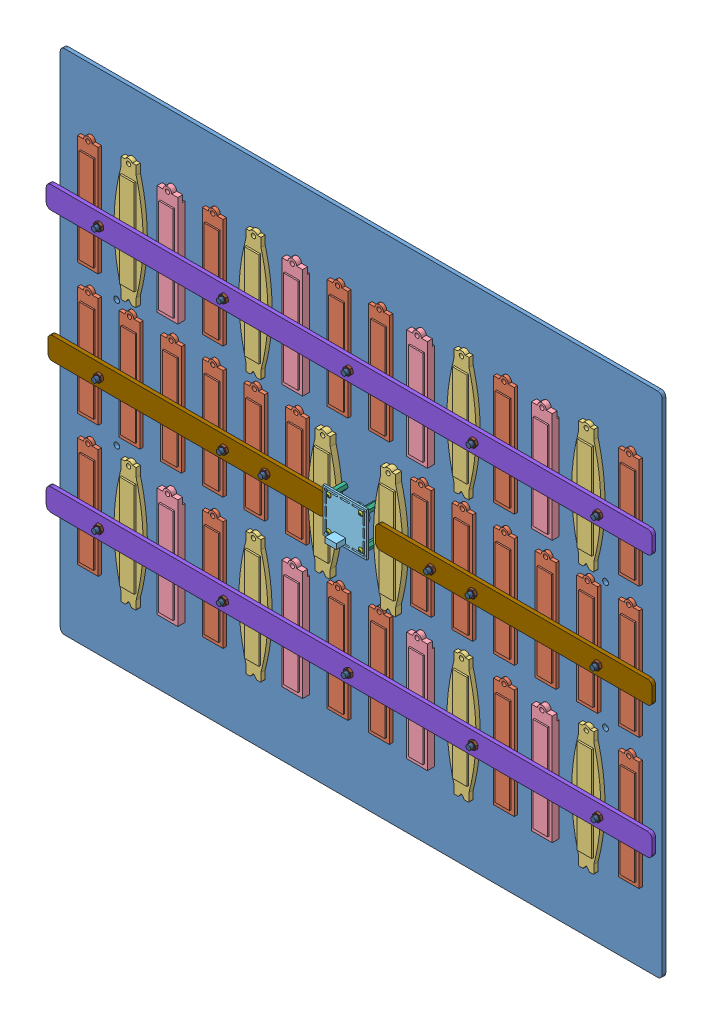
SolidWorks assembly light_panel_assembly, configuration Default. Lengths in mm.
Overall size (528.83 443.28 29.53).
93 component instances, 11 part files, 117 mates.
Components (placement in the parent):
- light_panel-2: light_panel [Default] at (-165.7065 6.3384 576.4657) size (525.46 443.28 3.17)
- ge_light_red-29: ge_light_red [Default] at (-258.0598 168.151 582.5617) x (0 1 0) z (-1 0 0) size (99.54 9.65 18.11)
- ge_light_red-30: ge_light_red [Default] at (-3.8058 168.151 582.5617) x (0 1 0) z (-1 0 0) size (99.54 9.65 18.11)
- ge_light_red-32: ge_light_red [Default] at (-149.0938 168.151 582.5617) x (0 1 0) z (-1 0 0) size (99.54 9.65 18.11)
- ge_light_red-34: ge_light_red [Default] at (-40.1278 168.151 582.5617) x (0 1 0) z (-1 0 0) size (99.54 9.65 18.11)
- ge_light_red-37: ge_light_red [Default] at (105.1602 168.151 582.5617) x (0 1 0) z (-1 0 0) size (99.54 9.65 18.11)
- ge_light_red-39: ge_light_red [Default] at (214.1262 168.151 582.5617) x (0 1 0) z (-1 0 0) size (99.54 9.65 18.11)
- ge_light_white-13: ge_light_white [Default] at (224.0604 93.1756 583.3237) x (1 0 0) z (0 0 -1) size (25.4 109.73 10.92)
- ge_light_white-15: ge_light_white [Default] at (-66.5156 93.1756 583.3237) x (1 0 0) z (0 0 -1) size (25.4 109.73 10.92)
- ge_light_red-43: ge_light_red [Default] at (214.1262 53.851 582.5617) x (0 1 0) z (-1 0 0) size (99.54 9.65 18.11)
- ge_light_red-44: ge_light_red [Default] at (-258.0598 53.851 582.5617) x (0 1 0) z (-1 0 0) size (99.54 9.65 18.11)
- ge_light_red-45: ge_light_red [Default] at (177.8042 53.851 582.5617) x (0 1 0) z (-1 0 0) size (99.54 9.65 18.11)
- ge_light_red-46: ge_light_red [Default] at (141.4822 53.851 582.5617) x (0 1 0) z (-1 0 0) size (99.54 9.65 18.11)
- ge_light_red-47: ge_light_red [Default] at (105.1602 53.851 582.5617) x (0 1 0) z (-1 0 0) size (99.54 9.65 18.11)
- ge_light_red-48: ge_light_red [Default] at (68.8382 53.851 582.5617) x (0 1 0) z (-1 0 0) size (99.54 9.65 18.11)
- ge_light_red-49: ge_light_red [Default] at (32.5162 53.851 582.5617) x (0 1 0) z (-1 0 0) size (99.54 9.65 18.11)
- ge_light_red-50: ge_light_red [Default] at (-221.7378 53.851 582.5617) x (0 1 0) z (-1 0 0) size (99.54 9.65 18.11)
- ge_light_red-51: ge_light_red [Default] at (-185.4158 53.851 582.5617) x (0 1 0) z (-1 0 0) size (99.54 9.65 18.11)
- ge_light_red-52: ge_light_red [Default] at (-149.0938 53.851 582.5617) x (0 1 0) z (-1 0 0) size (99.54 9.65 18.11)
- ge_light_red-53: ge_light_red [Default] at (-112.7718 53.851 582.5617) x (0 1 0) z (-1 0 0) size (99.54 9.65 18.11)
- ge_light_red-54: ge_light_red [Default] at (-76.4498 53.851 582.5617) x (0 1 0) z (-1 0 0) size (99.54 9.65 18.11)
- ge_light_blue-1: ge_light_blue [Default] at (141.4822 168.151 585.7367) x (0 1 0) z (-1 0 0) size (99.54 9.65 18.11)
- ge_light_blue-10: ge_light_blue [Default] at (32.5162 168.151 585.7367) x (0 1 0) z (-1 0 0) size (99.54 9.65 18.11)
- ge_light_blue-12: ge_light_blue [Default] at (-76.4498 168.151 585.7367) x (0 1 0) z (-1 0 0) size (99.54 9.65 18.11)
- ge_light_blue-14: ge_light_blue [Default] at (-185.4158 168.151 585.7367) x (0 1 0) z (-1 0 0) size (99.54 9.65 18.11)
- ELP_cam_assembly_lightpanel-1: ELP_cam_assembly_lightpanel [Default] at (-3.1026 -48.3745 609.8224) x (1 0 0) z (0 1 0) size (38.1 29.53 38.1)
  - ELP_cam-1: ELP_cam [Default] at (259.2408 15.8942 -284.1444) size (38.1 29.53 38.1)
  - 2-56 .5in  .1875 female-female standoff-2: 2-56 .5in  .1875 female-female standoff [91115A107] at (20.619 23.8317 45.4988) x (1 0 0) z (0 1 0) size (4.76 5.5 13.32)
  - 2-56 .5in  .1875 female-female standoff-3: 2-56 .5in  .1875 female-female standoff [91115A107] at (20.619 23.8317 17.5588) x (0.982082 0 -0.188455) z (0 1 0) size (4.76 5.5 13.32)
  - 2-56 .5in  .1875 female-female standoff-5: 2-56 .5in  .1875 female-female standoff [91115A107] at (-7.321 23.8317 17.5588) x (0.918365 0 -0.395734) z (0 1 0) size (4.76 5.5 13.32)
  - 2-56 .5in  .1875 female-female standoff-7: 2-56 .5in  .1875 female-female standoff [91115A107] at (-7.321 23.8317 45.4988) x (0.8 0 -0.6) z (0 1 0) size (4.76 5.5 13.32)
  - S-002-025-BTN-H-SS-001-256x1_4-button-head-screw-1: S-002-025-BTN-H-SS-001-256x1_4-button-head-screw [Default] at (-7.321 33.3567 17.5588) size (4.17 7.52 4.17)
  - S-002-025-BTN-H-SS-001-256x1_4-button-head-screw-2: S-002-025-BTN-H-SS-001-256x1_4-button-head-screw [Default] at (-7.321 33.3567 45.4988) x (0.982082 0 -0.188455) z (0.188455 0 0.982082) size (4.17 7.52 4.17)
  - S-002-025-BTN-H-SS-001-256x1_4-button-head-screw-4: S-002-025-BTN-H-SS-001-256x1_4-button-head-screw [Default] at (20.619 33.3567 45.4988) x (0.918365 0 -0.395734) z (0.395734 0 0.918365) size (4.17 7.52 4.17)
  - S-002-025-BTN-H-SS-001-256x1_4-button-head-screw-6: S-002-025-BTN-H-SS-001-256x1_4-button-head-screw [Default] at (20.619 33.3567 17.5588) x (0.8 0 -0.6) z (0.6 0 0.8) size (4.17 7.52 4.17)
  - S-002-025-BTN-H-SS-001-256x1_4-button-head-screw-11: S-002-025-BTN-H-SS-001-256x1_4-button-head-screw [Default] at (-7.321 15.8942 45.4988) x (-0.837169 0 -0.546944) z (-0.546944 0 0.837169) size (4.17 7.52 4.17)
  - S-002-025-BTN-H-SS-001-256x1_4-button-head-screw-12: S-002-025-BTN-H-SS-001-256x1_4-button-head-screw [Default] at (-7.321 15.8942 17.5588) x (-0.925243 0 -0.379375) z (-0.379375 0 0.925243) size (4.17 7.52 4.17)
  - S-002-025-BTN-H-SS-001-256x1_4-button-head-screw-13: S-002-025-BTN-H-SS-001-256x1_4-button-head-screw [Default] at (20.619 15.8942 17.5588) x (-0.985271 0 -0.170998) z (-0.170998 0 0.985271) size (4.17 7.52 4.17)
  - S-002-025-BTN-H-SS-001-256x1_4-button-head-screw-14: S-002-025-BTN-H-SS-001-256x1_4-button-head-screw [Default] at (20.619 15.8942 45.4988) x (-0.997902 0 0.064746) z (0.064746 0 0.997902) size (4.17 7.52 4.17)
- ge_light_white-25: ge_light_white [Default] at (52.4834 -25.9504 584.7207) x (1 0 0) z (0 0 -1) size (25.4 109.73 10.92)
- ge_light_white-26: ge_light_white [Default] at (-4.6666 -25.9504 584.7207) x (1 0 0) z (0 0 -1) size (25.4 109.73 10.92)
- ge_light_white-27: ge_light_white [Default] at (115.0944 93.1756 583.3237) x (1 0 0) z (0 0 -1) size (25.4 109.73 10.92)
- ge_light_white-28: ge_light_white [Default] at (-175.4816 93.1756 583.3237) x (1 0 0) z (0 0 -1) size (25.4 109.73 10.92)
- ge_light_blue-16: ge_light_blue [Default] at (32.5162 -60.449 585.7367) x (0 1 0) z (-1 0 0) size (99.54 9.65 18.11)
- ge_light_white-29: ge_light_white [Default] at (115.0944 -135.4244 583.3237) x (1 0 0) z (0 0 -1) size (25.4 109.73 10.92)
- ge_light_red-55: ge_light_red [Default] at (105.1602 -60.449 582.5617) x (0 1 0) z (-1 0 0) size (99.54 9.65 18.11)
- ge_light_blue-17: ge_light_blue [Default] at (141.4822 -60.449 585.7367) x (0 1 0) z (-1 0 0) size (99.54 9.65 18.11)
- ge_light_white-30: ge_light_white [Default] at (224.0604 -135.4244 583.3237) x (1 0 0) z (0 0 -1) size (25.4 109.73 10.92)
- ge_light_red-56: ge_light_red [Default] at (214.1262 -60.449 582.5617) x (0 1 0) z (-1 0 0) size (99.54 9.65 18.11)
- ge_light_red-57: ge_light_red [Default] at (-3.8058 -60.449 582.5617) x (0 1 0) z (-1 0 0) size (99.54 9.65 18.11)
- ge_light_red-58: ge_light_red [Default] at (-40.1278 -60.449 582.5617) x (0 1 0) z (-1 0 0) size (99.54 9.65 18.11)
- ge_light_blue-18: ge_light_blue [Default] at (-76.4498 -60.449 585.7367) x (0 1 0) z (-1 0 0) size (99.54 9.65 18.11)
- ge_light_white-31: ge_light_white [Default] at (-66.5156 -135.4244 583.3237) x (1 0 0) z (0 0 -1) size (25.4 109.73 10.92)
- ge_light_red-59: ge_light_red [Default] at (-149.0938 -60.449 582.5617) x (0 1 0) z (-1 0 0) size (99.54 9.65 18.11)
- ge_light_blue-19: ge_light_blue [Default] at (-185.4158 -60.449 585.7367) x (0 1 0) z (-1 0 0) size (99.54 9.65 18.11)
- ge_light_white-32: ge_light_white [Default] at (-175.4816 -135.4244 583.3237) x (1 0 0) z (0 0 -1) size (25.4 109.73 10.92)
- ge_light_red-60: ge_light_red [Default] at (-258.0598 -60.449 582.5617) x (0 1 0) z (-1 0 0) size (99.54 9.65 18.11)
- light_strap-1: light_strap [Default] at (-260.8675 87.2308 587.0067) size (528.83 19.43 3.17)
- light_strap-2: light_strap [Default] at (-260.8675 -141.3692 587.0067) size (528.83 19.43 3.17)
- light_strap_short-1: light_strap_short [Default] at (-260.1055 -27.0692 586.2447) size (241.3 19.43 3.17)
- light_strap_short-2: light_strap_short [Default] at (267.1985 -7.6382 586.2447) x (-1 0 0) z (0 0 1) size (241.3 19.43 3.17)
- S-008-075-BTN-H-SS-001-832x3_4-button-head-screw-1: S-008-075-BTN-H-SS-001-832x3_4-button-head-screw [Default] at (-214.0045 96.9463 576.4657) x (1 0 0) z (0 1 0) size (7.92 21.26 7.92)
- S-008-075-BTN-H-SS-001-832x3_4-button-head-screw-2: S-008-075-BTN-H-SS-001-832x3_4-button-head-screw [Default] at (-105.0385 96.9463 576.4657) x (0.987351 0.158553 0) z (-0.158553 0.987351 0) size (7.92 21.26 7.92)
- S-008-075-BTN-H-SS-001-832x3_4-button-head-screw-3: S-008-075-BTN-H-SS-001-832x3_4-button-head-screw [Default] at (3.9275 96.9463 576.4657) x (0.959125 0.282984 0) z (-0.282984 0.959125 0) size (7.92 21.26 7.92)
- S-008-075-BTN-H-SS-001-832x3_4-button-head-screw-4: S-008-075-BTN-H-SS-001-832x3_4-button-head-screw [Default] at (221.8595 96.9463 576.4657) x (0.928571 0.371154 0) z (-0.371154 0.928571 0) size (7.92 21.26 7.92)
- S-008-075-BTN-H-SS-001-832x3_4-button-head-screw-5: S-008-075-BTN-H-SS-001-832x3_4-button-head-screw [Default] at (221.0975 -17.3537 576.4657) x (0.906989 0.421154 0) z (-0.421154 0.906989 0) size (7.92 21.26 7.92)
- S-008-075-BTN-H-SS-001-832x3_4-button-head-screw-6: S-008-075-BTN-H-SS-001-832x3_4-button-head-screw [Default] at (75.8095 -17.3537 576.4657) x (0.902849 0.429957 0) z (-0.429957 0.902849 0) size (7.92 21.26 7.92)
- S-008-075-BTN-H-SS-001-832x3_4-button-head-screw-7: S-008-075-BTN-H-SS-001-832x3_4-button-head-screw [Default] at (-214.0045 -17.3537 576.4657) x (0.919615 0.39282 0) z (-0.39282 0.919615 0) size (7.92 21.26 7.92)
- S-008-075-BTN-H-SS-001-832x3_4-button-head-screw-8: S-008-075-BTN-H-SS-001-832x3_4-button-head-screw [Default] at (-105.0385 -17.3537 576.4657) x (0.952324 0.305088 0) z (-0.305088 0.952324 0) size (7.92 21.26 7.92)
- S-008-075-BTN-H-SS-001-832x3_4-button-head-screw-9: S-008-075-BTN-H-SS-001-832x3_4-button-head-screw [Default] at (-105.0385 -131.6537 576.4657) x (0.985697 0.168526 0) z (-0.168526 0.985697 0) size (7.92 21.26 7.92)
- S-008-075-BTN-H-SS-001-832x3_4-button-head-screw-10: S-008-075-BTN-H-SS-001-832x3_4-button-head-screw [Default] at (3.9275 -131.6537 576.4657) x (1 0 0) z (0 1 0) size (7.92 21.26 7.92)
- S-008-075-BTN-H-SS-001-832x3_4-button-head-screw-11: S-008-075-BTN-H-SS-001-832x3_4-button-head-screw [Default] at (112.8935 -131.6537 576.4657) x (0.985697 -0.168526 0) z (0.168526 0.985697 0) size (7.92 21.26 7.92)
- S-008-075-BTN-H-SS-001-832x3_4-button-head-screw-12: S-008-075-BTN-H-SS-001-832x3_4-button-head-screw [Default] at (221.8595 -131.6537 576.4657) x (0.952324 -0.305088 0) z (0.305088 0.952324 0) size (7.92 21.26 7.92)
- S-008-075-BTN-H-SS-001-832x3_4-button-head-screw-14: S-008-075-BTN-H-SS-001-832x3_4-button-head-screw [Default] at (112.8935 96.9463 576.4657) x (1 0 0) z (0 1 0) size (7.92 21.26 7.92)
- S-008-075-BTN-H-SS-001-832x3_4-button-head-screw-15: S-008-075-BTN-H-SS-001-832x3_4-button-head-screw [Default] at (112.1315 -17.3537 576.4657) x (0.987351 0.158553 0) z (-0.158553 0.987351 0) size (7.92 21.26 7.92)
- S-008-075-BTN-H-SS-001-832x3_4-button-head-screw-16: S-008-075-BTN-H-SS-001-832x3_4-button-head-screw [Default] at (-68.7165 -17.3537 576.4657) x (0.959125 0.282984 0) z (-0.282984 0.959125 0) size (7.92 21.26 7.92)
- S-008-075-BTN-H-SS-001-832x3_4-button-head-screw-17: S-008-075-BTN-H-SS-001-832x3_4-button-head-screw [Default] at (-214.0045 -131.6537 576.4657) x (0.928571 0.371154 0) z (-0.371154 0.928571 0) size (7.92 21.26 7.92)
- S-008-NUT-SS-001_832-SS-Nut-3-32thk-13: S-008-NUT-SS-001_832-SS-Nut-3-32thk [Default] at (112.8935 96.9463 590.1817) x (0.902124 0.431476 0) z (0.431476 -0.902124 0) size (6.35 2.38 7.33)
- S-008-NUT-SS-001_832-SS-Nut-3-32thk-14: S-008-NUT-SS-001_832-SS-Nut-3-32thk [Default] at (112.1315 -17.3537 590.1817) x (0.839841 0.542833 0) z (0.542833 -0.839841 0) size (6.35 2.38 7.33)
- S-008-NUT-SS-001_832-SS-Nut-3-32thk-15: S-008-NUT-SS-001_832-SS-Nut-3-32thk [Default] at (-68.7165 -17.3537 590.1817) x (0.785585 0.618753 0) z (0.618753 -0.785585 0) size (6.35 2.38 7.33)
- S-008-NUT-SS-001_832-SS-Nut-3-32thk-1: S-008-NUT-SS-001_832-SS-Nut-3-32thk [Default] at (-214.0045 96.9463 590.1817) x (1 0 0) z (0 -1 0) size (6.35 2.38 7.33)
- S-008-NUT-SS-001_832-SS-Nut-3-32thk-2: S-008-NUT-SS-001_832-SS-Nut-3-32thk [Default] at (-105.0385 96.9463 590.1817) x (0.987351 0.158553 0) z (0.158553 -0.987351 0) size (6.35 2.38 7.33)
- S-008-NUT-SS-001_832-SS-Nut-3-32thk-3: S-008-NUT-SS-001_832-SS-Nut-3-32thk [Default] at (3.9275 96.9463 590.1817) x (0.959125 0.282984 0) z (0.282984 -0.959125 0) size (6.35 2.38 7.33)
- S-008-NUT-SS-001_832-SS-Nut-3-32thk-4: S-008-NUT-SS-001_832-SS-Nut-3-32thk [Default] at (221.8595 96.9463 590.1817) x (0.928571 0.371154 0) z (0.371154 -0.928571 0) size (6.35 2.38 7.33)
- S-008-NUT-SS-001_832-SS-Nut-3-32thk-5: S-008-NUT-SS-001_832-SS-Nut-3-32thk [Default] at (221.0975 -17.3537 590.1817) x (0.906989 0.421154 0) z (0.421154 -0.906989 0) size (6.35 2.38 7.33)
- S-008-NUT-SS-001_832-SS-Nut-3-32thk-6: S-008-NUT-SS-001_832-SS-Nut-3-32thk [Default] at (75.8095 -17.3537 590.1817) x (0.902849 0.429957 0) z (0.429957 -0.902849 0) size (6.35 2.38 7.33)
- S-008-NUT-SS-001_832-SS-Nut-3-32thk-7: S-008-NUT-SS-001_832-SS-Nut-3-32thk [Default] at (-105.0385 -17.3537 590.1817) x (0.919615 0.39282 0) z (0.39282 -0.919615 0) size (6.35 2.38 7.33)
- S-008-NUT-SS-001_832-SS-Nut-3-32thk-8: S-008-NUT-SS-001_832-SS-Nut-3-32thk [Default] at (-214.0045 -17.3537 590.1817) x (0.952324 0.305088 0) z (0.305088 -0.952324 0) size (6.35 2.38 7.33)
- S-008-NUT-SS-001_832-SS-Nut-3-32thk-9: S-008-NUT-SS-001_832-SS-Nut-3-32thk [Default] at (-105.0385 -131.6537 590.1817) x (0.985697 0.168526 0) z (0.168526 -0.985697 0) size (6.35 2.38 7.33)
- S-008-NUT-SS-001_832-SS-Nut-3-32thk-10: S-008-NUT-SS-001_832-SS-Nut-3-32thk [Default] at (3.9275 -131.6537 590.1817) x (1 0 0) z (0 -1 0) size (6.35 2.38 7.33)
- S-008-NUT-SS-001_832-SS-Nut-3-32thk-11: S-008-NUT-SS-001_832-SS-Nut-3-32thk [Default] at (112.8935 -131.6537 590.1817) x (0.985697 -0.168526 0) z (-0.168526 -0.985697 0) size (6.35 2.38 7.33)
- S-008-NUT-SS-001_832-SS-Nut-3-32thk-12: S-008-NUT-SS-001_832-SS-Nut-3-32thk [Default] at (221.8595 -131.6537 590.1817) x (0.206834 0.978376 0) z (0.978376 -0.206834 0) size (6.35 2.38 7.33)
- S-008-NUT-SS-001_832-SS-Nut-3-32thk-18: S-008-NUT-SS-001_832-SS-Nut-3-32thk [Default] at (-214.0045 -131.6537 590.1817) x (0.891905 0.452222 0) z (0.452222 -0.891905 0) size (6.35 2.38 7.33)
Mates (geometry in assembly coordinates):
- Coincident1: coincident anti-aligned: plane of light_panel-2 through (-165.7065 6.3384 576.4657) normal (0 0 -1); plane of ? through (-206.3983 190.249 576.4657) normal (0 0 1)
- Parallel1: parallel aligned: plane of light_panel-2 through (-285.4801 231.0811 579.6407) normal (0 1 0); plane of ? through (-241.3476 164.0023 574.6877) normal (0 1 0)
- Concentric1: concentric aligned: circle of light_panel-2; circle of ?
- Coincident4: coincident aligned: circle of light_panel-2; circle of ?
- Parallel2: parallel aligned: plane of light_panel-2 through (-285.4801 231.0811 579.6407) normal (-1 0 0); plane of ? through (-244.9925 46.4003 579.6407) normal (-1 0 0)
- Coincident6: coincident anti-aligned: plane of light_panel-2 through (-165.7065 6.3384 576.4657) normal (0 0 -1); plane of ? through (-206.3983 164.849 576.4657) normal (0 0 1)
- Parallel3: parallel aligned: plane of light_panel-2 through (-285.4801 231.0811 579.6407) normal (0 1 0); plane of ? through (-228.5068 144.4443 569.0997) normal (0 1 0)
- Concentric2: concentric aligned: circle of light_panel-2; circle of ?
- Concentric3: concentric aligned: circle of light_panel-2; circle of ?
- Coincident10: coincident anti-aligned: plane of light_panel-2 through (-165.7065 6.3384 576.4657) normal (0 0 -1); plane of ? through (56.7457 164.849 576.4657) normal (0 0 1)
- Parallel5: parallel aligned: plane of light_panel-2 through (-285.4801 231.0811 579.6407) normal (0 1 0); plane of ? through (21.7964 144.4443 569.0997) normal (0 1 0)
- Coincident13: coincident anti-aligned: plane of light_panel-2 through (-165.7065 6.3384 576.4657) normal (0 0 -1); plane of ? through (-206.3983 50.549 576.4657) normal (0 0 1)
- Concentric4: concentric aligned: circle of light_panel-2; circle of ?
- Parallel6: parallel aligned: plane of light_panel-2 through (-285.4801 -264.7726 579.6407) normal (0 -1 0); plane of ? through (-241.3476 -65.6137 576.4657) normal (0 -1 0)
- Coincident16: coincident anti-aligned: plane of light_panel-2 through (-165.7065 6.3384 576.4657) normal (0 0 -1); plane of ? through (-268.7833 -9.9313 576.4657) normal (0 0 1)
- Concentric5: concentric aligned: circle of light_panel-2; circle of ?
- Coincident18: coincident anti-aligned: plane of light_panel-2 through (-165.7065 6.3384 576.4657) normal (0 0 -1); plane of ? through (-215.0625 88.3496 576.4657) normal (0 0 1)
- Parallel7: parallel anti-aligned: plane of light_panel-2 through (-285.4801 231.0811 579.6407) normal (0 1 0); plane of ? through (-182.0005 46.4003 574.6877) normal (0 -1 0)
- Parallel8: parallel anti-aligned: plane of ge_light_red-29 through (-223.1104 51.9883 576.4657) normal (0 -1 0); plane of light_panel-2 through (-259.1848 204.7921 576.4657) normal (0 1 0)
- Coincident24: coincident aligned: plane of light_panel-2 through (-165.7065 6.3384 576.4657) normal (0 0 -1); plane of ge_light_white-13 through (224.0604 93.1756 576.4657) normal (0 0 -1)
- Parallel9: parallel aligned: plane of ge_light_white-13 through (210.3025 151.5563 583.3237) normal (0 1 0); plane of light_panel-2 through (-259.1848 204.7921 576.4657) normal (0 1 0)
- Coincident26: coincident anti-aligned: plane of light_panel-2 through (-165.7065 6.3384 579.6407) normal (0 0 1); plane of ? through (42.4504 -25.9504 579.6407) normal (0 0 -1)
- Concentric8: concentric anti-aligned: circle of light_panel-2; circle of ?
- Parallel11: parallel aligned: plane of light_panel-2 through (-285.4801 231.0811 579.6407) normal (0 1 0); plane of ? through (28.6925 32.4303 584.7207) normal (0 1 0)
- Coincident31: coincident aligned: plane of light_panel-2 through (-165.7065 6.3384 576.4657) normal (0 0 -1); plane of ge_light_red-29 through (-258.0598 168.151 576.4657) normal (0 0 -1)
- Coincident32: coincident anti-aligned: plane of light_panel-2 through (-165.7065 6.3384 579.6407) normal (0 0 1); plane of ge_light_blue-14 through (-185.4158 168.151 579.6407) normal (0 0 -1)
- Parallel12: parallel aligned: plane of ge_light_blue-1 through (176.4316 147.7463 587.0067) normal (0 1 0); plane of light_panel-2 through (-259.1848 204.7921 576.4657) normal (0 1 0)
- Concentric10: concentric: circle of light_panel-2; circle of ?
- Coincident34: coincident: plane of light_panel-2 through (-165.7065 6.3384 576.4657) normal (0 0 -1); plane of ? through (52.4834 -25.9504 576.4657) normal (0 0 -1)
- Parallel13: parallel aligned: plane of light_panel-2 through (-285.4801 231.0811 579.6407) normal (0 1 0); plane of ? through (19.4215 24.8103 576.4657) normal (0 1 0)
- Concentric11: concentric: circle of light_panel-2; circle of ?
- Parallel14: parallel: plane of light_panel-2 through (-285.4801 231.0811 579.6407) normal (0 1 0); plane of ? through (16.2465 24.8103 576.4657) normal (0 1 0)
- Coincident39: coincident anti-aligned: plane of light_panel-2 through (-165.7065 6.3384 579.6407) normal (0 0 1); plane of ? through (49.3084 -25.9504 579.6407) normal (0 0 -1)
- Concentric12: concentric anti-aligned: circle of light_panel-2; circle of ?
- Concentric13: concentric anti-aligned: circle of light_panel-2; circle of ?
- Coincident40: coincident anti-aligned: plane of light_panel-2 through (-165.7065 6.3384 579.6407) normal (0 0 1); plane of ? through (15.2146 -4.3796 579.6407) normal (0 0 -1)
- Coincident42: coincident anti-aligned: plane of light_panel-2 through (-165.7065 6.3384 579.6407) normal (0 0 1); plane of ge_light_white-25 through (52.4834 -25.9504 579.6407) normal (0 0 -1)
- Parallel15: parallel aligned: plane of ge_light_white-25 through (19.4215 24.8103 579.6407) normal (0 1 0); plane of light_panel-2 through (-259.1848 204.7921 576.4657) normal (0 1 0)
- Concentric17: concentric anti-aligned: cylinder of light_panel-2 through (-86.8775 -169.2457 579.6407) axis (0 0 -1) radius 3.5719; cylinder of ge_light_white-31 through (-86.8775 -169.2457 573.9257) axis (0 0 1) radius 3.81
- Concentric18: concentric anti-aligned: cylinder of light_panel-2 through (-232.1655 -169.7537 579.6407) axis (0 0 -1) radius 3.9688; cylinder of ge_light_red-60 through (-232.1655 -169.7537 574.1797) axis (0 0 1) radius 3.81
- Concentric19: concentric anti-aligned: cylinder of light_panel-2 through (-159.5215 -169.7537 579.6407) axis (0 0 -1) radius 3.9688; cylinder of ge_light_blue-19 through (-159.5215 -169.7537 577.3547) axis (0 0 1) radius 3.81
- Concentric20: concentric anti-aligned: cylinder of light_panel-2 through (-214.0045 96.9463 576.4657) axis (0 0 -1) radius 2.2479; cylinder of light_strap-1 through (-214.0045 96.9463 590.1817) axis (0 0 1) radius 2.2479
- Concentric21: concentric anti-aligned: cylinder of light_panel-2 through (221.8595 -131.6537 576.4657) axis (0 0 -1) radius 2.2479; cylinder of light_strap-2 through (221.8595 -131.6537 590.1817) axis (0 0 1) radius 2.2479
- Concentric23: concentric anti-aligned: cylinder of light_panel-2 through (221.8595 96.9463 576.4657) axis (0 0 -1) radius 2.2479; cylinder of light_strap-1 through (221.8595 96.9463 590.1817) axis (0 0 1) radius 2.2479
- Concentric24: concentric anti-aligned: cylinder of light_panel-2 through (-214.0045 -131.6537 576.4657) axis (0 0 -1) radius 2.2479; cylinder of light_strap-2 through (-214.0045 -131.6537 590.1817) axis (0 0 1) radius 2.2479
- Coincident45: coincident anti-aligned: plane of ge_light_blue-19 through (-185.4158 -60.449 587.0067) normal (0 0 1); plane of light_strap-2 through (-260.8675 -141.3692 587.0067) normal (0 0 -1)
- Coincident46: coincident anti-aligned: plane of ge_light_blue-14 through (-185.4158 168.151 587.0067) normal (0 0 1); plane of light_strap-1 through (-260.8675 87.2308 587.0067) normal (0 0 -1)
- Concentric25: concentric aligned: cylinder of light_panel-2 through (-214.0045 -17.3537 579.6407) axis (0 0 1) radius 2.2479; cylinder of light_strap_short-1 through (-214.0045 -17.3537 589.4197) axis (0 0 1) radius 2.2479
- Concentric26: concentric aligned: cylinder of light_panel-2 through (-105.0385 -17.3537 579.6407) axis (0 0 1) radius 2.2479; cylinder of light_strap_short-1 through (-105.0385 -17.3537 589.4197) axis (0 0 1) radius 2.2479
- Coincident47: coincident anti-aligned: plane of ge_light_white-26 through (-4.6666 -25.9504 586.2447) normal (0 0 1); plane of light_strap_short-1 through (-260.1055 -27.0692 586.2447) normal (0 0 -1)
- Concentric27: concentric aligned: cylinder of light_panel-2 through (221.0975 -17.3537 579.6407) axis (0 0 1) radius 2.2479; cylinder of light_strap_short-2 through (221.0975 -17.3537 589.4197) axis (0 0 1) radius 2.2479
- Concentric28: concentric aligned: cylinder of light_panel-2 through (112.1315 -17.3537 579.6407) axis (0 0 1) radius 2.2479; cylinder of light_strap_short-2 through (112.1315 -17.3537 589.4197) axis (0 0 1) radius 2.2479
- Coincident48: coincident anti-aligned: plane of ge_light_white-25 through (52.4834 -25.9504 586.2447) normal (0 0 1); plane of light_strap_short-2 through (267.1985 -7.6382 586.2447) normal (0 0 -1)
- Concentric29: concentric anti-aligned: cylinder of light_panel-2 through (-214.0045 96.9463 576.4657) axis (0 0 -1) radius 2.2479; cylinder of S-008-075-BTN-H-SS-001-832x3_4-button-head-screw-1 through (-214.0045 96.9463 595.5157) axis (0 0 1) radius 2.0828
- Coincident49: coincident anti-aligned: plane of light_panel-2 through (-165.7065 6.3384 576.4657) normal (0 0 -1); plane of S-008-075-BTN-H-SS-001-832x3_4-button-head-screw-1 through (-216.0873 96.9463 576.4657) normal (0 0 1)
- Coincident51: coincident anti-aligned: plane of light_panel-2 through (-165.7065 6.3384 576.4657) normal (0 0 -1); plane of S-008-075-BTN-H-SS-001-832x3_4-button-head-screw-2 through (-107.095 96.6161 576.4657) normal (0 0 1)
- Concentric30: concentric anti-aligned: cylinder of light_panel-2 through (-105.0385 96.9463 576.4657) axis (0 0 -1) radius 2.2479; cylinder of S-008-075-BTN-H-SS-001-832x3_4-button-head-screw-2 through (-105.0385 96.9463 595.5157) axis (0 0 1) radius 2.0828
- Coincident52: coincident anti-aligned: plane of light_panel-2 through (-165.7065 6.3384 576.4657) normal (0 0 -1); plane of S-008-075-BTN-H-SS-001-832x3_4-button-head-screw-3 through (1.9298 96.3569 576.4657) normal (0 0 1)
- Concentric31: concentric anti-aligned: cylinder of light_panel-2 through (3.9275 96.9463 576.4657) axis (0 0 -1) radius 2.2479; cylinder of S-008-075-BTN-H-SS-001-832x3_4-button-head-screw-3 through (3.9275 96.9463 595.5157) axis (0 0 1) radius 2.0828
- Coincident53: coincident anti-aligned: plane of light_panel-2 through (-165.7065 6.3384 576.4657) normal (0 0 -1); plane of S-008-075-BTN-H-SS-001-832x3_4-button-head-screw-4 through (219.9254 96.1732 576.4657) normal (0 0 1)
- Concentric32: concentric anti-aligned: cylinder of light_panel-2 through (221.8595 96.9463 576.4657) axis (0 0 -1) radius 2.2479; cylinder of S-008-075-BTN-H-SS-001-832x3_4-button-head-screw-4 through (221.8595 96.9463 595.5157) axis (0 0 1) radius 2.0828
- Coincident54: coincident anti-aligned: plane of light_panel-2 through (-165.7065 6.3384 576.4657) normal (0 0 -1); plane of S-008-075-BTN-H-SS-001-832x3_4-button-head-screw-5 through (219.2084 -18.2309 576.4657) normal (0 0 1)
- Concentric33: concentric aligned: cylinder of light_panel-2 through (221.0975 -17.3537 579.6407) axis (0 0 1) radius 2.2479; cylinder of S-008-075-BTN-H-SS-001-832x3_4-button-head-screw-5 through (221.0975 -17.3537 595.5157) axis (0 0 1) radius 2.0828
- Coincident55: coincident anti-aligned: plane of light_panel-2 through (-165.7065 6.3384 576.4657) normal (0 0 -1); plane of S-008-075-BTN-H-SS-001-832x3_4-button-head-screw-6 through (73.929 -18.2492 576.4657) normal (0 0 1)
- Concentric34: concentric aligned: cylinder of light_panel-2 through (75.8095 -17.3537 579.6407) axis (0 0 1) radius 2.2479; cylinder of S-008-075-BTN-H-SS-001-832x3_4-button-head-screw-6 through (75.8095 -17.3537 595.5157) axis (0 0 1) radius 2.0828
- Coincident56: coincident anti-aligned: plane of light_panel-2 through (-165.7065 6.3384 576.4657) normal (0 0 -1); plane of S-008-075-BTN-H-SS-001-832x3_4-button-head-screw-7 through (-215.9199 -18.1719 576.4657) normal (0 0 1)
- Concentric35: concentric aligned: cylinder of light_panel-2 through (-214.0045 -17.3537 579.6407) axis (0 0 1) radius 2.2479; cylinder of S-008-075-BTN-H-SS-001-832x3_4-button-head-screw-7 through (-214.0045 -17.3537 595.5157) axis (0 0 1) radius 2.0828
- Coincident57: coincident anti-aligned: plane of light_panel-2 through (-165.7065 6.3384 576.4657) normal (0 0 -1); plane of S-008-075-BTN-H-SS-001-832x3_4-button-head-screw-8 through (-107.022 -17.9892 576.4657) normal (0 0 1)
- Concentric36: concentric aligned: cylinder of light_panel-2 through (-105.0385 -17.3537 579.6407) axis (0 0 1) radius 2.2479; cylinder of S-008-075-BTN-H-SS-001-832x3_4-button-head-screw-8 through (-105.0385 -17.3537 595.5157) axis (0 0 1) radius 2.0828
- Coincident58: coincident anti-aligned: plane of light_panel-2 through (-165.7065 6.3384 576.4657) normal (0 0 -1); plane of S-008-075-BTN-H-SS-001-832x3_4-button-head-screw-9 through (-107.0915 -132.0047 576.4657) normal (0 0 1)
- Concentric37: concentric anti-aligned: cylinder of light_panel-2 through (-105.0385 -131.6537 576.4657) axis (0 0 -1) radius 2.2479; cylinder of S-008-075-BTN-H-SS-001-832x3_4-button-head-screw-9 through (-105.0385 -131.6537 595.5157) axis (0 0 1) radius 2.0828
- Coincident59: coincident anti-aligned: plane of light_panel-2 through (-165.7065 6.3384 576.4657) normal (0 0 -1); plane of S-008-075-BTN-H-SS-001-832x3_4-button-head-screw-10 through (1.8447 -131.6537 576.4657) normal (0 0 1)
- Concentric38: concentric anti-aligned: cylinder of light_panel-2 through (3.9275 -131.6537 576.4657) axis (0 0 -1) radius 2.2479; cylinder of S-008-075-BTN-H-SS-001-832x3_4-button-head-screw-10 through (3.9275 -131.6537 595.5157) axis (0 0 1) radius 2.0828
- Coincident60: coincident anti-aligned: plane of light_panel-2 through (-165.7065 6.3384 576.4657) normal (0 0 -1); plane of S-008-075-BTN-H-SS-001-832x3_4-button-head-screw-11 through (110.8405 -131.3027 576.4657) normal (0 0 1)
- Concentric39: concentric anti-aligned: cylinder of light_panel-2 through (112.8935 -131.6537 576.4657) axis (0 0 -1) radius 2.2479; cylinder of S-008-075-BTN-H-SS-001-832x3_4-button-head-screw-11 through (112.8935 -131.6537 595.5157) axis (0 0 1) radius 2.0828
- Coincident61: coincident anti-aligned: plane of light_panel-2 through (-165.7065 6.3384 576.4657) normal (0 0 -1); plane of S-008-075-BTN-H-SS-001-832x3_4-button-head-screw-12 through (219.876 -131.0183 576.4657) normal (0 0 1)
- Concentric40: concentric anti-aligned: cylinder of light_panel-2 through (221.8595 -131.6537 576.4657) axis (0 0 -1) radius 2.2479; cylinder of S-008-075-BTN-H-SS-001-832x3_4-button-head-screw-12 through (221.8595 -131.6537 595.5157) axis (0 0 1) radius 2.0828
- Concentric41: concentric anti-aligned: cylinder of S-008-075-BTN-H-SS-001-832x3_4-button-head-screw-1 through (-214.0045 96.9463 595.5157) axis (0 0 1) radius 2.0828; cylinder of S-008-NUT-SS-001_832-SS-Nut-3-32thk-1 through (-214.0045 96.9463 592.563) axis (0 0 -1) radius 2.1828
- Coincident64: coincident anti-aligned: plane of light_strap-1 through (-260.8675 87.2308 590.1817) normal (0 0 1); plane of S-008-NUT-SS-001_832-SS-Nut-3-32thk-1 through (-214.0045 96.9463 590.1817) normal (0 0 -1)
- Coincident65: coincident anti-aligned: plane of light_strap-1 through (-260.8675 87.2308 590.1817) normal (0 0 1); plane of S-008-NUT-SS-001_832-SS-Nut-3-32thk-2 through (-105.0385 96.9463 590.1817) normal (0 0 -1)
- Concentric42: concentric anti-aligned: cylinder of S-008-075-BTN-H-SS-001-832x3_4-button-head-screw-2 through (-105.0385 96.9463 595.5157) axis (0 0 1) radius 2.0828; cylinder of S-008-NUT-SS-001_832-SS-Nut-3-32thk-2 through (-105.0385 96.9463 592.563) axis (0 0 -1) radius 2.1828
- Coincident66: coincident anti-aligned: plane of light_strap-1 through (-260.8675 87.2308 590.1817) normal (0 0 1); plane of S-008-NUT-SS-001_832-SS-Nut-3-32thk-3 through (3.9275 96.9463 590.1817) normal (0 0 -1)
- Concentric43: concentric anti-aligned: cylinder of S-008-075-BTN-H-SS-001-832x3_4-button-head-screw-3 through (3.9275 96.9463 595.5157) axis (0 0 1) radius 2.0828; cylinder of S-008-NUT-SS-001_832-SS-Nut-3-32thk-3 through (3.9275 96.9463 592.563) axis (0 0 -1) radius 2.1828
- Coincident67: coincident anti-aligned: plane of light_strap-1 through (-260.8675 87.2308 590.1817) normal (0 0 1); plane of S-008-NUT-SS-001_832-SS-Nut-3-32thk-4 through (221.8595 96.9463 590.1817) normal (0 0 -1)
- Concentric44: concentric anti-aligned: cylinder of S-008-075-BTN-H-SS-001-832x3_4-button-head-screw-4 through (221.8595 96.9463 595.5157) axis (0 0 1) radius 2.0828; cylinder of S-008-NUT-SS-001_832-SS-Nut-3-32thk-4 through (221.8595 96.9463 592.563) axis (0 0 -1) radius 2.1828
- Coincident68: coincident anti-aligned: plane of light_strap-1 through (-260.8675 87.2308 590.1817) normal (0 0 1); plane of S-008-NUT-SS-001_832-SS-Nut-3-32thk-5 through (221.0975 -17.3537 590.1817) normal (0 0 -1)
- Concentric45: concentric anti-aligned: cylinder of S-008-075-BTN-H-SS-001-832x3_4-button-head-screw-5 through (221.0975 -17.3537 595.5157) axis (0 0 1) radius 2.0828; cylinder of S-008-NUT-SS-001_832-SS-Nut-3-32thk-5 through (221.0975 -17.3537 592.563) axis (0 0 -1) radius 2.1828
- Coincident69: coincident anti-aligned: plane of light_strap-1 through (-260.8675 87.2308 590.1817) normal (0 0 1); plane of S-008-NUT-SS-001_832-SS-Nut-3-32thk-6 through (75.8095 -17.3537 590.1817) normal (0 0 -1)
- Concentric46: concentric anti-aligned: cylinder of S-008-075-BTN-H-SS-001-832x3_4-button-head-screw-6 through (75.8095 -17.3537 595.5157) axis (0 0 1) radius 2.0828; cylinder of S-008-NUT-SS-001_832-SS-Nut-3-32thk-6 through (75.8095 -17.3537 592.563) axis (0 0 -1) radius 2.1828
- Coincident70: coincident anti-aligned: plane of light_strap-1 through (-260.8675 87.2308 590.1817) normal (0 0 1); plane of S-008-NUT-SS-001_832-SS-Nut-3-32thk-7 through (-105.0385 -17.3537 590.1817) normal (0 0 -1)
- Concentric47: concentric anti-aligned: cylinder of S-008-075-BTN-H-SS-001-832x3_4-button-head-screw-8 through (-105.0385 -17.3537 595.5157) axis (0 0 1) radius 2.0828; cylinder of S-008-NUT-SS-001_832-SS-Nut-3-32thk-7 through (-105.0385 -17.3537 592.563) axis (0 0 -1) radius 2.1828
- Coincident71: coincident anti-aligned: plane of light_strap-1 through (-260.8675 87.2308 590.1817) normal (0 0 1); plane of S-008-NUT-SS-001_832-SS-Nut-3-32thk-8 through (-214.0045 -17.3537 590.1817) normal (0 0 -1)
- Concentric48: concentric anti-aligned: cylinder of S-008-075-BTN-H-SS-001-832x3_4-button-head-screw-7 through (-214.0045 -17.3537 595.5157) axis (0 0 1) radius 2.0828; cylinder of S-008-NUT-SS-001_832-SS-Nut-3-32thk-8 through (-214.0045 -17.3537 592.563) axis (0 0 -1) radius 2.1828
- Coincident72: coincident anti-aligned: plane of light_strap-1 through (-260.8675 87.2308 590.1817) normal (0 0 1); plane of S-008-NUT-SS-001_832-SS-Nut-3-32thk-9 through (-105.0385 -131.6537 590.1817) normal (0 0 -1)
- Concentric49: concentric anti-aligned: cylinder of S-008-075-BTN-H-SS-001-832x3_4-button-head-screw-9 through (-105.0385 -131.6537 595.5157) axis (0 0 1) radius 2.0828; cylinder of S-008-NUT-SS-001_832-SS-Nut-3-32thk-9 through (-105.0385 -131.6537 592.563) axis (0 0 -1) radius 2.1828
- Coincident73: coincident anti-aligned: plane of light_strap-1 through (-260.8675 87.2308 590.1817) normal (0 0 1); plane of S-008-NUT-SS-001_832-SS-Nut-3-32thk-10 through (3.9275 -131.6537 590.1817) normal (0 0 -1)
- Concentric50: concentric anti-aligned: cylinder of S-008-075-BTN-H-SS-001-832x3_4-button-head-screw-10 through (3.9275 -131.6537 595.5157) axis (0 0 1) radius 2.0828; cylinder of S-008-NUT-SS-001_832-SS-Nut-3-32thk-10 through (3.9275 -131.6537 592.563) axis (0 0 -1) radius 2.1828
- Coincident74: coincident anti-aligned: plane of light_strap-1 through (-260.8675 87.2308 590.1817) normal (0 0 1); plane of S-008-NUT-SS-001_832-SS-Nut-3-32thk-11 through (112.8935 -131.6537 590.1817) normal (0 0 -1)
- Concentric51: concentric anti-aligned: cylinder of S-008-075-BTN-H-SS-001-832x3_4-button-head-screw-11 through (112.8935 -131.6537 595.5157) axis (0 0 1) radius 2.0828; cylinder of S-008-NUT-SS-001_832-SS-Nut-3-32thk-11 through (112.8935 -131.6537 592.563) axis (0 0 -1) radius 2.1828
- Coincident75: coincident anti-aligned: plane of light_strap-1 through (-260.8675 87.2308 590.1817) normal (0 0 1); plane of S-008-NUT-SS-001_832-SS-Nut-3-32thk-12 through (221.8595 -131.6537 590.1817) normal (0 0 -1)
- Concentric52: concentric anti-aligned: cylinder of S-008-075-BTN-H-SS-001-832x3_4-button-head-screw-12 through (221.8595 -131.6537 595.5157) axis (0 0 1) radius 2.0828; cylinder of S-008-NUT-SS-001_832-SS-Nut-3-32thk-12 through (221.8595 -131.6537 592.563) axis (0 0 -1) radius 2.1828
- Coincident77: coincident anti-aligned: plane of light_panel-2 through (-165.7065 6.3384 576.4657) normal (0 0 -1); plane of S-008-075-BTN-H-SS-001-832x3_4-button-head-screw-14 through (110.8107 96.9463 576.4657) normal (0 0 1)
- Concentric54: concentric anti-aligned: cylinder of light_panel-2 through (112.8935 96.9463 576.4657) axis (0 0 -1) radius 2.2479; cylinder of S-008-075-BTN-H-SS-001-832x3_4-button-head-screw-14 through (112.8935 96.9463 595.5157) axis (0 0 1) radius 2.0828
- Coincident78: coincident anti-aligned: plane of light_panel-2 through (-165.7065 6.3384 576.4657) normal (0 0 -1); plane of S-008-075-BTN-H-SS-001-832x3_4-button-head-screw-15 through (110.075 -17.6839 576.4657) normal (0 0 1)
- Concentric55: concentric aligned: cylinder of light_panel-2 through (112.1315 -17.3537 579.6407) axis (0 0 1) radius 2.2479; cylinder of S-008-075-BTN-H-SS-001-832x3_4-button-head-screw-15 through (112.1315 -17.3537 595.5157) axis (0 0 1) radius 2.0828
- Coincident79: coincident anti-aligned: plane of light_panel-2 through (-165.7065 6.3384 576.4657) normal (0 0 -1); plane of S-008-075-BTN-H-SS-001-832x3_4-button-head-screw-16 through (-70.7142 -17.9431 576.4657) normal (0 0 1)
- Concentric56: concentric aligned: cylinder of light_panel-2 through (-68.7165 -17.3537 579.6407) axis (0 0 1) radius 2.2479; cylinder of S-008-075-BTN-H-SS-001-832x3_4-button-head-screw-16 through (-68.7165 -17.3537 595.5157) axis (0 0 1) radius 2.0828
- Coincident80: coincident anti-aligned: plane of light_panel-2 through (-165.7065 6.3384 576.4657) normal (0 0 -1); plane of S-008-075-BTN-H-SS-001-832x3_4-button-head-screw-17 through (-215.9386 -132.4268 576.4657) normal (0 0 1)
- Concentric57: concentric anti-aligned: cylinder of light_panel-2 through (-214.0045 -131.6537 576.4657) axis (0 0 -1) radius 2.2479; cylinder of S-008-075-BTN-H-SS-001-832x3_4-button-head-screw-17 through (-214.0045 -131.6537 595.5157) axis (0 0 1) radius 2.0828
- Coincident83: coincident anti-aligned: plane of light_strap-1 through (-260.8675 87.2308 590.1817) normal (0 0 1); plane of S-008-NUT-SS-001_832-SS-Nut-3-32thk-13 through (112.8935 96.9463 590.1817) normal (0 0 -1)
- Concentric58: concentric anti-aligned: cylinder of S-008-075-BTN-H-SS-001-832x3_4-button-head-screw-14 through (112.8935 96.9463 595.5157) axis (0 0 1) radius 2.0828; cylinder of S-008-NUT-SS-001_832-SS-Nut-3-32thk-13 through (112.8935 96.9463 592.563) axis (0 0 -1) radius 2.1828
- Coincident84: coincident anti-aligned: plane of light_strap-1 through (-260.8675 87.2308 590.1817) normal (0 0 1); plane of S-008-NUT-SS-001_832-SS-Nut-3-32thk-14 through (112.1315 -17.3537 590.1817) normal (0 0 -1)
- Concentric59: concentric anti-aligned: cylinder of S-008-075-BTN-H-SS-001-832x3_4-button-head-screw-15 through (112.1315 -17.3537 595.5157) axis (0 0 1) radius 2.0828; cylinder of S-008-NUT-SS-001_832-SS-Nut-3-32thk-14 through (112.1315 -17.3537 592.563) axis (0 0 -1) radius 2.1828
- Coincident85: coincident anti-aligned: plane of light_strap-1 through (-260.8675 87.2308 590.1817) normal (0 0 1); plane of S-008-NUT-SS-001_832-SS-Nut-3-32thk-15 through (-68.7165 -17.3537 590.1817) normal (0 0 -1)
- Concentric60: concentric anti-aligned: cylinder of S-008-075-BTN-H-SS-001-832x3_4-button-head-screw-16 through (-68.7165 -17.3537 595.5157) axis (0 0 1) radius 2.0828; cylinder of S-008-NUT-SS-001_832-SS-Nut-3-32thk-15 through (-68.7165 -17.3537 592.563) axis (0 0 -1) radius 2.1828
- Coincident88: coincident anti-aligned: plane of light_strap-1 through (-260.8675 87.2308 590.1817) normal (0 0 1); plane of S-008-NUT-SS-001_832-SS-Nut-3-32thk-18 through (-214.0045 -131.6537 590.1817) normal (0 0 -1)
- Concentric62: concentric anti-aligned: cylinder of S-008-075-BTN-H-SS-001-832x3_4-button-head-screw-17 through (-214.0045 -131.6537 595.5157) axis (0 0 1) radius 2.0828; cylinder of S-008-NUT-SS-001_832-SS-Nut-3-32thk-18 through (-214.0045 -131.6537 592.563) axis (0 0 -1) radius 2.1828
